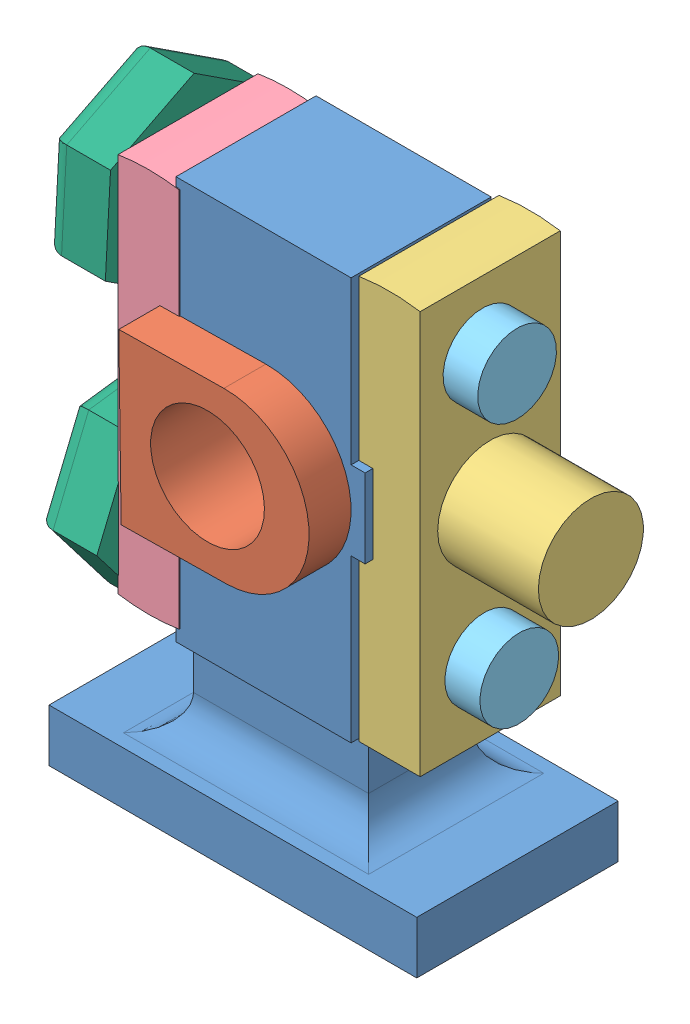
SolidWorks assembly CROSSHEAD, configuration Default. Lengths in mm.
Overall size (267.72 342.74 145.63).
8 component instances, 6 part files, 10 mates.
Components (placement in the parent):
- Body-1: Body [Default] at origin size (210 310 115)
- Brchssos-1: Brchssos [Default] at (19.2023 -0.457 -53.5214) x (0.999903 0.013932 0) z (0 0 1) size (108 96 130)
- piston rod cross head-1: piston rod cross head [Default] at (117.5 -0.0501 -4.435) size (92.5 231.4 80)
- keep plate-2: keep plate [Default] at (-15.1498 1.2481 0.4965) size (35 220 80)
- bolt crosshead-1: bolt crosshead [Default] at (154.7811 75 0) x (0 -0.572321 0.82003) z (-1 0 0) size (45 45 230)
- bolt crosshead-2: bolt crosshead [Default] at (156.0311 -75 0) x (0 0.668185 0.743995) z (-1 0 0) size (45 45 230)
- nut crosshead-1: nut crosshead [Default] at (-32.1949 -75 0) x (0 -0.840575 0.541695) z (-1 0 0) size (105.18 100.72 35)
- nut crosshead-3: nut crosshead [Default] at (-32.6178 75 0) x (0 0.689089 0.724676) z (-1 0 0) size (105.18 100.72 35)
Mates (geometry in assembly coordinates):
- Tangent1: tangent aligned: cylinder of Body-1 through (52 0 -40) axis (0 0 1) radius 40; cylinder of Brchssos-1 through (52 0 -1.0214) axis (0 0 -1) radius 40
- Coincident2: coincident anti-aligned: plane of Body-1 through (108 22.5 -40) normal (1 0 0); plane of piston rod cross head-1 through (108 -22.5501 -44.435) normal (-1 0 0)
- Coincident6: coincident aligned: axis of Body-1 through (0 75 0) axis (1 0 0); axis of bolt crosshead-1 through (-75.2189 75 0) axis (1 0 0)
- Tangent3: tangent: line of piston rod cross head-1 through (135 -116.4511 -44.435) axis (0 1 0); cylinder of bolt crosshead-1 through (134.7811 75 0) axis (1 0 0) radius 22.5
- Concentric2: concentric: axis of Body-1 through (0 -75 0) axis (1 0 0); cylinder of bolt crosshead-2 through (-73.9689 -75 0) axis (1 0 0) radius 15
- Concentric4: concentric: cylinder of piston rod cross head-1 through (-22.5 -75.0501 -4.435) axis (1 0 0) radius 16.5; circle of bolt crosshead-2
- Coincident10: coincident anti-aligned: axis of bolt crosshead-2 through (-73.9689 -75 0) axis (1 0 0); axis of nut crosshead-1 through (-32.1949 -75 0) axis (-1 0 0)
- Coincident11: coincident anti-aligned: axis of bolt crosshead-2 through (-73.9689 -75 0) axis (1 0 0); axis of nut crosshead-1 through (-32.1949 -75 0) axis (-1 0 0)
- Concentric5: concentric aligned: circle of bolt crosshead-2; cylinder of nut crosshead-1 through (17.8051 -75 0) axis (-1 0 0) radius 15
- Coincident20: coincident anti-aligned: axis of bolt crosshead-1 through (-75.2189 75 0) axis (1 0 0); axis of nut crosshead-3 through (-32.6178 75 0) axis (-1 0 0)
